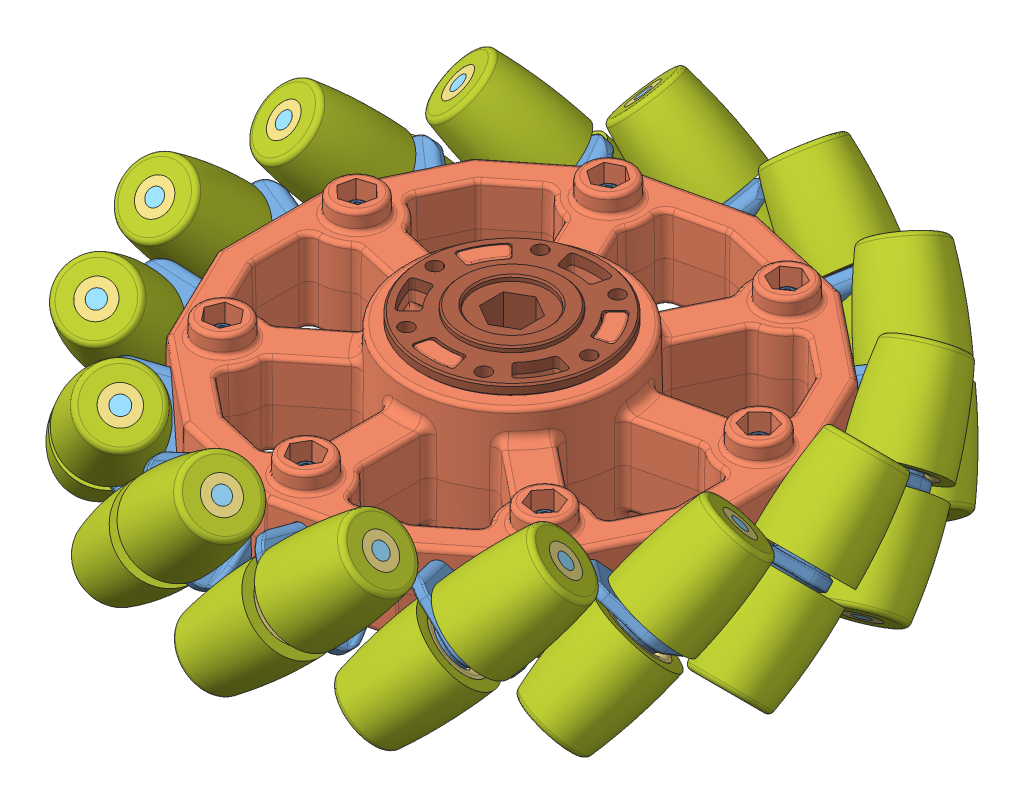
SolidWorks assembly 8in mecanum left vex 217-28011, configuration Default. Lengths in mm.
Overall size (213.38 67.99 218.38).
150 component instances, 12 part files, 7 mates.
Components (placement in the parent):
- 217-2799-002 Rev1_1-1: 217-2799-002 Rev1_1 [Default] at (67.5204 0 0) x (0 0 -1) z (1 0 0) size (26.84 25.28 30.09)
- 217-2801-001 Rev1_1-1: 217-2801-001 Rev1_1 [Default] at (-0.0396 6.3542 -0.0405) x (1 0 0) z (0 -1 0) size (148.4 151.99 28.55)
- 217-2801-001 Rev1_1-2: 217-2801-001 Rev1_1 [Default] at (-0.0396 -6.3458 -0.0405) x (-1 0 0) z (0 1 0) size (148.4 151.99 28.55)
- 217-2586-003 Rev2_1-1: 217-2586-003 Rev2_1 [Default] at (88.2976 -4.0062 4.0062) x (-0.854327 -0.367509 -0.367509) z (-0.519737 0.6041 0.6041) size (19.46 28.57 19.46)
- 217-2586-003 Rev2_1-2: 217-2586-003 Rev2_1 [Default] at (88.2976 4.0062 -4.0062) x (0.717269 -0.492709 -0.492709) z (0.696796 0.507186 0.507186) size (19.46 28.57 19.46)
- 217-2586-005 Rev2_1-1: 217-2586-005 Rev2_1 [Default] at (88.2976 -6.3286 6.3286) x (0 0.707107 -0.707107) z (0.473193 -0.622932 -0.622932) size (8.5 8 8)
- 217-2586-005 Rev2_1-2: 217-2586-005 Rev2_1 [Default] at (88.2976 6.3286 -6.3286) x (0 0.707107 -0.707107) z (0.707107 -0.5 -0.5) size (8.5 8 8)
- 217-2586-007 Rev1_1-1: 217-2586-007 Rev1_1 [Default] at (88.2976 0 0) x (0 0.707107 -0.707107) z (0.543569 -0.59352 -0.59352) size (61.72 5 5)
- 217-2586-008 Rev1_1-1: 217-2586-008 Rev1_1 [Default] at (-11.9459 2.5442 -20.6627) x (0.866025 0 -0.5) z (0 -1 0) size (7.33 6.35 31.75)
- 217-2587-002 Rev2_1-1: 217-2587-002 Rev2_1 [Default] at (88.2976 -0.3986 0.3986) x (-0.963241 0.189956 0.189956) z (-0.268638 -0.681114 -0.681114) size (26.1 28.57 26.1)
- 217-2587-002 Rev2_1-2: 217-2587-002 Rev2_1 [Default] at (88.2976 0.3986 -0.3986) x (0.779223 -0.443177 -0.443177) z (-0.626747 -0.550994 -0.550994) size (26.1 28.57 26.1)
- NUT-832-NYLOCK_1-1: NUT-832-NYLOCK_1 [Default] at (-49.6859 -13.6521 39.5511) x (-0.365341 0 0.930874) z (0.930874 0 0.365341) size (10.2 5.86 8.12)
- PINL-M050-0012-S_1-1: PINL-M050-0012-S_1 [Default] at (-69.318 -0.0958 -15.8528) x (0 -1 0) z (-0.272222 0 0.962235) size (12 5 5)
- SCREW-832-1250_1-1: SCREW-832-1250_1 [Default] at (-49.6859 14.914 39.5511) x (0 -1 0) z (-0.321403 0 -0.946943) size (33.96 7.92 7.92)
- 217-2586-008 Rev1_1-2: 217-2586-008 Rev1_1 [Default] at (-23.8521 2.5442 -0.0405) x (0 0 -1) z (0 -1 0) size (7.33 6.35 31.75)
- 217-2586-008 Rev1_1-3: 217-2586-008 Rev1_1 [Default] at (-11.9459 2.5442 20.5817) x (-0.866025 0 -0.5) z (0 -1 0) size (7.33 6.35 31.75)
- 217-2586-008 Rev1_1-4: 217-2586-008 Rev1_1 [Default] at (11.8666 2.5442 20.5817) x (-0.866025 0 0.5) z (0 -1 0) size (7.33 6.35 31.75)
- 217-2586-008 Rev1_1-5: 217-2586-008 Rev1_1 [Default] at (23.7729 2.5442 -0.0405) x (0 0 1) z (0 -1 0) size (7.33 6.35 31.75)
- 217-2586-008 Rev1_1-6: 217-2586-008 Rev1_1 [Default] at (11.8666 2.5442 -20.6627) x (0.866025 0 0.5) z (0 -1 0) size (7.33 6.35 31.75)
- NUT-832-NYLOCK_1-2: NUT-832-NYLOCK_1 [Default] at (-0.0396 -13.6521 63.4595) x (0.5 0 0.866025) z (0.866025 0 -0.5) size (10.2 5.86 8.12)
- NUT-832-NYLOCK_1-3: NUT-832-NYLOCK_1 [Default] at (49.6067 -13.6521 39.5511) x (0.988831 0 0.149042) z (0.149042 0 -0.988831) size (10.2 5.86 8.12)
- NUT-832-NYLOCK_1-4: NUT-832-NYLOCK_1 [Default] at (61.8683 -13.6521 -14.1706) x (0.733052 0 -0.680173) z (-0.680173 0 -0.733052) size (10.2 5.86 8.12)
- NUT-832-NYLOCK_1-5: NUT-832-NYLOCK_1 [Default] at (27.512 -13.6521 -57.252) x (-0.07473 0 -0.997204) z (-0.997204 0 0.07473) size (10.2 5.86 8.12)
- NUT-832-NYLOCK_1-6: NUT-832-NYLOCK_1 [Default] at (-27.5912 -13.6521 -57.252) x (-0.826239 0 -0.56332) z (-0.56332 0 0.826239) size (10.2 5.86 8.12)
- NUT-832-NYLOCK_1-7: NUT-832-NYLOCK_1 [Default] at (-61.9475 -13.6521 -14.1706) x (-0.955573 0 0.294755) z (0.294755 0 0.955573) size (10.2 5.86 8.12)
- SCREW-832-1250_1-2: SCREW-832-1250_1 [Default] at (-0.0396 14.914 63.4595) x (0 -1 0) z (-0.940741 0 -0.339126) size (33.96 7.92 7.92)
- SCREW-832-1250_1-3: SCREW-832-1250_1 [Default] at (49.6067 14.914 39.5511) x (0 -1 0) z (-0.851682 0 0.524059) size (33.96 7.92 7.92)
- SCREW-832-1250_1-4: SCREW-832-1250_1 [Default] at (61.8683 14.914 -14.1706) x (0 -1 0) z (-0.121289 0 0.992617) size (33.96 7.92 7.92)
- SCREW-832-1250_1-5: SCREW-832-1250_1 [Default] at (27.512 14.914 -57.252) x (0 -1 0) z (0.700437 0 0.713714) size (33.96 7.92 7.92)
- SCREW-832-1250_1-6: SCREW-832-1250_1 [Default] at (-27.5912 14.914 -57.252) x (0 -1 0) z (0.99472 0 -0.10263) size (33.96 7.92 7.92)
- SCREW-832-1250_1-7: SCREW-832-1250_1 [Default] at (-61.9475 14.914 -14.1706) x (0 -1 0) z (0.539958 0 -0.841692) size (33.96 7.92 7.92)
- PINL-M050-0012-S_1-2: PINL-M050-0012-S_1 [Default] at (-69.318 -0.0958 15.7719) x (0 -1 0) z (0.172235 0 0.985056) size (12 5 5)
- PINL-M050-0012-S_1-3: PINL-M050-0012-S_1 [Default] at (-55.5966 -0.0958 44.2647) x (0 -1 0) z (0.582578 0 0.812775) size (12 5 5)
- PINL-M050-0012-S_1-4: PINL-M050-0012-S_1 [Default] at (-30.8714 -0.0958 63.9824) x (0 -1 0) z (0.877534 0 0.479514) size (12 5 5)
- PINL-M050-0012-S_1-5: PINL-M050-0012-S_1 [Default] at (-0.0396 -0.0958 71.0195) x (0 -1 0) z (0.998684 0 0.051279) size (12 5 5)
- PINL-M050-0012-S_1-6: PINL-M050-0012-S_1 [Default] at (30.7922 -0.0958 63.9824) x (0 -1 0) z (0.922033 0 -0.387112) size (12 5 5)
- PINL-M050-0012-S_1-7: PINL-M050-0012-S_1 [Default] at (55.5173 -0.0958 44.2647) x (0 -1 0) z (0.662761 0 -0.748831) size (12 5 5)
- PINL-M050-0012-S_1-8: PINL-M050-0012-S_1 [Default] at (69.2388 -0.0958 15.7719) x (0 -1 0) z (0.272222 0 -0.962235) size (12 5 5)
- PINL-M050-0012-S_1-9: PINL-M050-0012-S_1 [Default] at (69.2388 -0.0958 -15.8528) x (0 -1 0) z (-0.172235 0 -0.985056) size (12 5 5)
- PINL-M050-0012-S_1-10: PINL-M050-0012-S_1 [Default] at (55.5173 -0.0958 -44.3457) x (0 -1 0) z (-0.582578 0 -0.812775) size (12 5 5)
- PINL-M050-0012-S_1-11: PINL-M050-0012-S_1 [Default] at (30.7922 -0.0958 -64.0633) x (0 -1 0) z (-0.877534 0 -0.479514) size (12 5 5)
- PINL-M050-0012-S_1-12: PINL-M050-0012-S_1 [Default] at (-0.0396 -0.0958 -71.1005) x (0 -1 0) z (-0.998684 0 -0.051279) size (12 5 5)
- PINL-M050-0012-S_1-13: PINL-M050-0012-S_1 [Default] at (-30.8714 -0.0958 -64.0633) x (0 -1 0) z (-0.922033 0 0.387112) size (12 5 5)
- PINL-M050-0012-S_1-14: PINL-M050-0012-S_1 [Default] at (-55.5966 -0.0958 -44.3457) x (0 -1 0) z (-0.662761 0 0.748831) size (12 5 5)
- 217-2587-002 Rev2_1-3: 217-2587-002 Rev2_1 [Default] at (79.3941 0.3986 -38.6912) x (0.509769 -0.443177 -0.737381) z (-0.803746 -0.550994 -0.224493) size (26.1 28.57 26.1)
- 217-2587-002 Rev2_1-4: 217-2587-002 Rev2_1 [Default] at (54.7578 0.3986 -69.3286) x (0.139348 -0.443177 -0.885537) z (-0.821555 -0.550994 0.146471) size (26.1 28.57 26.1)
- 217-2587-002 Rev2_1-5: 217-2587-002 Rev2_1 [Default] at (19.2682 0.3986 -86.2426) x (-0.258672 -0.443177 -0.858303) z (-0.676644 -0.550994 0.488425) size (26.1 28.57 26.1)
- 217-2587-002 Rev2_1-6: 217-2587-002 Rev2_1 [Default] at (-20.0456 0.3986 -86.0832) x (-0.605459 -0.443177 -0.66107) z (-0.397715 -0.550994 0.73364) size (26.1 28.57 26.1)
- 217-2587-002 Rev2_1-7: 217-2587-002 Rev2_1 [Default] at (-55.3969 0.3986 -68.882) x (-0.832327 -0.443177 -0.332905) z (-0.040014 -0.550994 0.833549) size (26.1 28.57 26.1)
- 217-2587-002 Rev2_1-8: 217-2587-002 Rev2_1 [Default] at (-79.784 0.3986 -38.0459) x (-0.894343 -0.443177 0.061196) z (0.325612 -0.550994 0.768364) size (26.1 28.57 26.1)
- 217-2587-002 Rev2_1-9: 217-2587-002 Rev2_1 [Default] at (-88.3768 0.3986 0.3176) x (-0.779223 -0.443177 0.443177) z (0.626747 -0.550994 0.550994) size (26.1 28.57 26.1)
- 217-2587-002 Rev2_1-10: 217-2587-002 Rev2_1 [Default] at (-79.4733 0.3986 38.6102) x (-0.509769 -0.443177 0.737381) z (0.803746 -0.550994 0.224493) size (26.1 28.57 26.1)
- 217-2587-002 Rev2_1-11: 217-2587-002 Rev2_1 [Default] at (-54.837 0.3986 69.2476) x (-0.139348 -0.443177 0.885537) z (0.821555 -0.550994 -0.146471) size (26.1 28.57 26.1)
- 217-2587-002 Rev2_1-12: 217-2587-002 Rev2_1 [Default] at (-19.3474 0.3986 86.1616) x (0.258672 -0.443177 0.858303) z (0.676644 -0.550994 -0.488425) size (26.1 28.57 26.1)
- 217-2587-002 Rev2_1-13: 217-2587-002 Rev2_1 [Default] at (19.9664 0.3986 86.0022) x (0.605459 -0.443177 0.66107) z (0.397715 -0.550994 -0.73364) size (26.1 28.57 26.1)
- 217-2587-002 Rev2_1-14: 217-2587-002 Rev2_1 [Default] at (55.3177 0.3986 68.8011) x (0.832327 -0.443177 0.332905) z (0.040014 -0.550994 -0.833549) size (26.1 28.57 26.1)
- 217-2587-002 Rev2_1-15: 217-2587-002 Rev2_1 [Default] at (79.7048 0.3986 37.965) x (0.894343 -0.443177 -0.061196) z (-0.325612 -0.550994 -0.768364) size (26.1 28.57 26.1)
- 217-2587-002 Rev2_1-16: 217-2587-002 Rev2_1 [Default] at (79.74 -0.3986 -37.973) x (-0.785432 0.189956 0.589079) z (-0.537559 -0.681114 -0.497105) size (26.1 28.57 26.1)
- 217-2587-002 Rev2_1-17: 217-2587-002 Rev2_1 [Default] at (55.381 -0.3986 -68.8315) x (-0.452058 0.189956 0.871528) z (-0.70001 -0.681114 -0.214638) size (26.1 28.57 26.1)
- 217-2587-002 Rev2_1-18: 217-2587-002 Rev2_1 [Default] at (20.0453 -0.3986 -86.0652) x (-0.029148 0.189956 0.98136) z (-0.723815 -0.681114 0.110341) size (26.1 28.57 26.1)
- 217-2587-002 Rev2_1-19: 217-2587-002 Rev2_1 [Default] at (-19.2684 -0.3986 -86.2606) x (0.399535 0.189956 0.896822) z (-0.60426 -0.681114 0.413465) size (26.1 28.57 26.1)
- 217-2587-002 Rev2_1-20: 217-2587-002 Rev2_1 [Default] at (-54.7737 -0.3986 -69.379) x (0.749084 0.189956 0.634657) z (-0.365024 -0.681114 0.634698) size (26.1 28.57 26.1)
- 217-2587-002 Rev2_1-21: 217-2587-002 Rev2_1 [Default] at (-79.4382 -0.3986 -38.7641) x (0.950269 0.189956 0.24679) z (-0.05349 -0.681114 0.730221) size (26.1 28.57 26.1)
- 217-2587-002 Rev2_1-22: 217-2587-002 Rev2_1 [Default] at (-88.3768 -0.3986 -0.4795) x (0.963241 0.189956 -0.189956) z (0.268638 -0.681114 0.681114) size (26.1 28.57 26.1)
- 217-2587-002 Rev2_1-23: 217-2587-002 Rev2_1 [Default] at (-79.8192 -0.3986 37.892) x (0.785432 0.189956 -0.589079) z (0.537559 -0.681114 0.497105) size (26.1 28.57 26.1)
- 217-2587-002 Rev2_1-24: 217-2587-002 Rev2_1 [Default] at (-55.4602 -0.3986 68.7506) x (0.452058 0.189956 -0.871528) z (0.70001 -0.681114 0.214638) size (26.1 28.57 26.1)
- 217-2587-002 Rev2_1-25: 217-2587-002 Rev2_1 [Default] at (-20.1245 -0.3986 85.9842) x (0.029148 0.189956 -0.98136) z (0.723815 -0.681114 -0.110341) size (26.1 28.57 26.1)
- 217-2587-002 Rev2_1-26: 217-2587-002 Rev2_1 [Default] at (19.1892 -0.3986 86.1796) x (-0.399535 0.189956 -0.896822) z (0.60426 -0.681114 -0.413465) size (26.1 28.57 26.1)
- 217-2587-002 Rev2_1-27: 217-2587-002 Rev2_1 [Default] at (54.6945 -0.3986 69.2981) x (-0.749084 0.189956 -0.634657) z (0.365024 -0.681114 -0.634698) size (26.1 28.57 26.1)
- 217-2587-002 Rev2_1-28: 217-2587-002 Rev2_1 [Default] at (79.359 -0.3986 38.6832) x (-0.950269 0.189956 -0.24679) z (0.05349 -0.681114 -0.730221) size (26.1 28.57 26.1)
- 217-2586-007 Rev1_1-2: 217-2586-007 Rev1_1 [Default] at (79.567 0 -38.3321) x (-0.306802 0.707107 -0.637081) z (0.23222 -0.59352 -0.770589) size (61.72 5 5)
- 217-2586-007 Rev1_1-3: 217-2586-007 Rev1_1 [Default] at (55.0694 0 -69.08) x (-0.552838 0.707107 -0.440874) z (-0.125123 -0.59352 -0.795033) size (61.72 5 5)
- 217-2586-007 Rev1_1-4: 217-2586-007 Rev1_1 [Default] at (19.6567 0 -86.1539) x (-0.689378 0.707107 -0.157346) z (-0.457684 -0.59352 -0.662011) size (61.72 5 5)
- 217-2586-007 Rev1_1-5: 217-2586-007 Rev1_1 [Default] at (-19.657 0 -86.1719) x (-0.689378 0.707107 0.157346) z (-0.699595 -0.59352 -0.39787) size (61.72 5 5)
- 217-2586-007 Rev1_1-6: 217-2586-007 Rev1_1 [Default] at (-55.0853 0 -69.1305) x (-0.552838 0.707107 0.440874) z (-0.802943 -0.59352 -0.054926) size (61.72 5 5)
- 217-2586-007 Rev1_1-7: 217-2586-007 Rev1_1 [Default] at (-79.6111 0 -38.405) x (-0.306802 0.707107 0.637081) z (-0.747258 -0.59352 0.298897) size (61.72 5 5)
- 217-2586-007 Rev1_1-8: 217-2586-007 Rev1_1 [Default] at (-88.3768 0 -0.081) x (0 0.707107 0.707107) z (-0.543569 -0.59352 0.59352) size (61.72 5 5)
- 217-2586-007 Rev1_1-9: 217-2586-007 Rev1_1 [Default] at (-79.6462 0 38.2511) x (0.306802 0.707107 0.637081) z (-0.23222 -0.59352 0.770589) size (61.72 5 5)
- 217-2586-007 Rev1_1-10: 217-2586-007 Rev1_1 [Default] at (-55.1486 0 68.9991) x (0.552838 0.707107 0.440874) z (0.125123 -0.59352 0.795033) size (61.72 5 5)
- 217-2586-007 Rev1_1-11: 217-2586-007 Rev1_1 [Default] at (-19.736 0 86.0729) x (0.689378 0.707107 0.157346) z (0.457684 -0.59352 0.662011) size (61.72 5 5)
- 217-2586-007 Rev1_1-12: 217-2586-007 Rev1_1 [Default] at (19.5778 0 86.0909) x (0.689378 0.707107 -0.157346) z (0.699595 -0.59352 0.39787) size (61.72 5 5)
- 217-2586-007 Rev1_1-13: 217-2586-007 Rev1_1 [Default] at (55.0061 0 69.0496) x (0.552838 0.707107 -0.440874) z (0.802943 -0.59352 0.054926) size (61.72 5 5)
- 217-2586-007 Rev1_1-14: 217-2586-007 Rev1_1 [Default] at (79.5319 0 38.3241) x (0.306802 0.707107 -0.637081) z (0.747258 -0.59352 -0.298897) size (61.72 5 5)
- 217-2586-005 Rev2_1-3: 217-2586-005 Rev2_1 [Default] at (76.8211 6.3286 -44.034) x (-0.306802 0.707107 -0.637081) z (0.420139 -0.5 -0.757287) size (8.5 8 8)
- 217-2586-005 Rev2_1-4: 217-2586-005 Rev2_1 [Default] at (50.1215 6.3286 -73.0259) x (-0.552838 0.707107 -0.440874) z (0.049958 -0.5 -0.864583) size (8.5 8 8)
- 217-2586-005 Rev2_1-5: 217-2586-005 Rev2_1 [Default] at (13.4868 6.3286 -87.5621) x (-0.689378 0.707107 -0.157346) z (-0.330118 -0.5 -0.800639) size (8.5 8 8)
- 217-2586-005 Rev2_1-6: 217-2586-005 Rev2_1 [Default] at (-25.827 6.3286 -84.7636) x (-0.689378 0.707107 0.157346) z (-0.64481 -0.5 -0.578118) size (8.5 8 8)
- 217-2586-005 Rev2_1-7: 217-2586-005 Rev2_1 [Default] at (-60.0332 6.3286 -65.1847) x (-0.552838 0.707107 0.440874) z (-0.83179 -0.5 -0.241093) size (8.5 8 8)
- 217-2586-005 Rev2_1-8: 217-2586-005 Rev2_1 [Default] at (-82.357 6.3286 -32.7032) x (-0.306802 0.707107 0.637081) z (-0.854023 -0.5 0.143682) size (8.5 8 8)
- 217-2586-005 Rev2_1-9: 217-2586-005 Rev2_1 [Default] at (-88.3768 6.3286 6.2476) x (0 0.707107 0.707107) z (-0.707107 -0.5 0.5) size (8.5 8 8)
- 217-2586-005 Rev2_1-10: 217-2586-005 Rev2_1 [Default] at (-76.9004 6.3286 43.953) x (0.306802 0.707107 0.637081) z (-0.420139 -0.5 0.757287) size (8.5 8 8)
- 217-2586-005 Rev2_1-11: 217-2586-005 Rev2_1 [Default] at (-50.2007 6.3286 72.9449) x (0.552838 0.707107 0.440874) z (-0.049958 -0.5 0.864583) size (8.5 8 8)
- 217-2586-005 Rev2_1-12: 217-2586-005 Rev2_1 [Default] at (-13.566 6.3286 87.4812) x (0.689378 0.707107 0.157346) z (0.330118 -0.5 0.800639) size (8.5 8 8)
- 217-2586-005 Rev2_1-13: 217-2586-005 Rev2_1 [Default] at (25.7477 6.3286 84.6827) x (0.689378 0.707107 -0.157346) z (0.64481 -0.5 0.578118) size (8.5 8 8)
- 217-2586-005 Rev2_1-14: 217-2586-005 Rev2_1 [Default] at (59.954 6.3286 65.1037) x (0.552838 0.707107 -0.440874) z (0.83179 -0.5 0.241093) size (8.5 8 8)
- 217-2586-005 Rev2_1-15: 217-2586-005 Rev2_1 [Default] at (82.2778 6.3286 32.6222) x (0.306802 0.707107 -0.637081) z (0.854023 -0.5 -0.143682) size (8.5 8 8)
- 217-2586-005 Rev2_1-16: 217-2586-005 Rev2_1 [Default] at (82.3129 -6.3286 -32.6302) x (-0.306802 0.707107 -0.637081) z (0.156052 -0.622932 -0.766553) size (8.5 8 8)
- 217-2586-005 Rev2_1-17: 217-2586-005 Rev2_1 [Default] at (60.0173 -6.3286 -65.1342) x (-0.552838 0.707107 -0.440874) z (-0.191997 -0.622932 -0.758349) size (8.5 8 8)
- 217-2586-005 Rev2_1-18: 217-2586-005 Rev2_1 [Default] at (25.8267 -6.3286 -84.7456) x (-0.689378 0.707107 -0.157346) z (-0.502019 -0.622932 -0.599944) size (8.5 8 8)
- 217-2586-005 Rev2_1-19: 217-2586-005 Rev2_1 [Default] at (-13.4871 -6.3286 -87.5801) x (-0.689378 0.707107 0.157346) z (-0.712609 -0.622932 -0.322713) size (8.5 8 8)
- 217-2586-005 Rev2_1-20: 217-2586-005 Rev2_1 [Default] at (-50.1374 -6.3286 -73.0764) x (-0.552838 0.707107 0.440874) z (-0.782059 -0.622932 0.018435) size (8.5 8 8)
- 217-2586-005 Rev2_1-21: 217-2586-005 Rev2_1 [Default] at (-76.8652 -6.3286 -44.1069) x (-0.306802 0.707107 0.637081) z (-0.696612 -0.622932 0.355932) size (8.5 8 8)
- 217-2586-005 Rev2_1-22: 217-2586-005 Rev2_1 [Default] at (-88.3768 -6.3286 -6.4096) x (0 0.707107 0.707107) z (-0.473193 -0.622932 0.622932) size (8.5 8 8)
- 217-2586-005 Rev2_1-23: 217-2586-005 Rev2_1 [Default] at (-82.3921 -6.3286 32.5492) x (0.306802 0.707107 0.637081) z (-0.156052 -0.622932 0.766553) size (8.5 8 8)
- 217-2586-005 Rev2_1-24: 217-2586-005 Rev2_1 [Default] at (-60.0965 -6.3286 65.0533) x (0.552838 0.707107 0.440874) z (0.191997 -0.622932 0.758349) size (8.5 8 8)
- 217-2586-005 Rev2_1-25: 217-2586-005 Rev2_1 [Default] at (-25.9059 -6.3286 84.6647) x (0.689378 0.707107 0.157346) z (0.502019 -0.622932 0.599944) size (8.5 8 8)
- 217-2586-005 Rev2_1-26: 217-2586-005 Rev2_1 [Default] at (13.4079 -6.3286 87.4992) x (0.689378 0.707107 -0.157346) z (0.712609 -0.622932 0.322713) size (8.5 8 8)
- 217-2586-005 Rev2_1-27: 217-2586-005 Rev2_1 [Default] at (50.0582 -6.3286 72.9954) x (0.552838 0.707107 -0.440874) z (0.782059 -0.622932 -0.018435) size (8.5 8 8)
- 217-2586-005 Rev2_1-28: 217-2586-005 Rev2_1 [Default] at (76.786 -6.3286 44.0259) x (0.306802 0.707107 -0.637081) z (0.696612 -0.622932 -0.355932) size (8.5 8 8)
- 217-2586-003 Rev2_1-3: 217-2586-003 Rev2_1 [Default] at (77.8288 4.0062 -41.9416) x (0.432459 -0.492709 -0.755127) z (0.847851 0.507186 0.15463) size (19.46 28.57 19.46)
- 217-2586-003 Rev2_1-4: 217-2586-003 Rev2_1 [Default] at (51.9372 4.0062 -71.5779) x (0.061995 -0.492709 -0.867983) z (0.830979 0.507186 -0.228552) size (19.46 28.57 19.46)
- 217-2586-003 Rev2_1-5: 217-2586-003 Rev2_1 [Default] at (15.7509 4.0062 -87.0453) x (-0.320749 -0.492709 -0.808924) z (0.649521 0.507186 -0.566466) size (19.46 28.57 19.46)
- 217-2586-003 Rev2_1-6: 217-2586-003 Rev2_1 [Default] at (-23.5628 4.0062 -85.2804) x (-0.639963 -0.492709 -0.589648) z (0.339418 0.507186 -0.792185) size (19.46 28.57 19.46)
- 217-2586-003 Rev2_1-7: 217-2586-003 Rev2_1 [Default] at (-58.2175 4.0062 -66.6327) x (-0.832426 -0.492709 -0.253585) z (-0.037911 0.507186 -0.861002) size (19.46 28.57 19.46)
- 217-2586-003 Rev2_1-8: 217-2586-003 Rev2_1 [Default] at (-81.3494 4.0062 -34.7955) x (-0.860016 -0.492709 0.132704) z (-0.407732 0.507186 -0.759287) size (19.46 28.57 19.46)
- 217-2586-003 Rev2_1-9: 217-2586-003 Rev2_1 [Default] at (-88.3768 4.0062 3.9253) x (-0.717269 -0.492709 0.492709) z (-0.696796 0.507186 -0.507186) size (19.46 28.57 19.46)
- 217-2586-003 Rev2_1-10: 217-2586-003 Rev2_1 [Default] at (-77.908 4.0062 41.8606) x (-0.432459 -0.492709 0.755127) z (-0.847851 0.507186 -0.15463) size (19.46 28.57 19.46)
- 217-2586-003 Rev2_1-11: 217-2586-003 Rev2_1 [Default] at (-52.0164 4.0062 71.4969) x (-0.061995 -0.492709 0.867983) z (-0.830979 0.507186 0.228552) size (19.46 28.57 19.46)
- 217-2586-003 Rev2_1-12: 217-2586-003 Rev2_1 [Default] at (-15.8302 4.0062 86.9644) x (0.320749 -0.492709 0.808924) z (-0.649521 0.507186 0.566466) size (19.46 28.57 19.46)
- 217-2586-003 Rev2_1-13: 217-2586-003 Rev2_1 [Default] at (23.4836 4.0062 85.1995) x (0.639963 -0.492709 0.589648) z (-0.339418 0.507186 0.792185) size (19.46 28.57 19.46)
- 217-2586-003 Rev2_1-14: 217-2586-003 Rev2_1 [Default] at (58.1383 4.0062 66.5517) x (0.832426 -0.492709 0.253585) z (0.037911 0.507186 0.861002) size (19.46 28.57 19.46)
- 217-2586-003 Rev2_1-15: 217-2586-003 Rev2_1 [Default] at (81.2701 4.0062 34.7146) x (0.860016 -0.492709 -0.132704) z (0.407732 0.507186 0.759287) size (19.46 28.57 19.46)
- 217-2586-003 Rev2_1-16: 217-2586-003 Rev2_1 [Default] at (81.3053 -4.0062 -34.7226) x (-0.929178 -0.367509 0.039564) z (-0.206157 0.6041 0.769781) size (19.46 28.57 19.46)
- 217-2586-003 Rev2_1-17: 217-2586-003 Rev2_1 [Default] at (58.2016 -4.0062 -66.5822) x (-0.819994 -0.367509 0.438801) z (0.148254 0.6041 0.782997) size (19.46 28.57 19.46)
- 217-2586-003 Rev2_1-18: 217-2586-003 Rev2_1 [Default] at (23.5625 -4.0062 -85.2624) x (-0.548401 -0.367509 0.751128) z (0.473302 0.6041 0.641131) size (19.46 28.57 19.46)
- 217-2586-003 Rev2_1-19: 217-2586-003 Rev2_1 [Default] at (-15.7512 -4.0062 -87.0634) x (-0.16819 -0.367509 0.914685) z (0.704606 0.6041 0.372281) size (19.46 28.57 19.46)
- 217-2586-003 Rev2_1-20: 217-2586-003 Rev2_1 [Default] at (-51.9531 -4.0062 -71.6284) x (0.245334 -0.367509 0.897078) z (0.796355 0.6041 0.029696) size (19.46 28.57 19.46)
- 217-2586-003 Rev2_1-21: 217-2586-003 Rev2_1 [Default] at (-77.8729 -4.0062 -42.0145) x (0.610265 -0.367509 0.701793) z (0.730376 0.6041 -0.31877) size (19.46 28.57 19.46)
- 217-2586-003 Rev2_1-22: 217-2586-003 Rev2_1 [Default] at (-88.3768 -4.0062 -4.0872) x (0.854327 -0.367509 0.367509) z (0.519737 0.6041 -0.6041) size (19.46 28.57 19.46)
- 217-2586-003 Rev2_1-23: 217-2586-003 Rev2_1 [Default] at (-81.3845 -4.0062 34.6416) x (0.929178 -0.367509 -0.039564) z (0.206157 0.6041 -0.769781) size (19.46 28.57 19.46)
- 217-2586-003 Rev2_1-24: 217-2586-003 Rev2_1 [Default] at (-58.2808 -4.0062 66.5012) x (0.819994 -0.367509 -0.438801) z (-0.148254 0.6041 -0.782997) size (19.46 28.57 19.46)
- 217-2586-003 Rev2_1-25: 217-2586-003 Rev2_1 [Default] at (-23.6417 -4.0062 85.1814) x (0.548401 -0.367509 -0.751128) z (-0.473302 0.6041 -0.641131) size (19.46 28.57 19.46)
- 217-2586-003 Rev2_1-26: 217-2586-003 Rev2_1 [Default] at (15.672 -4.0062 86.9824) x (0.16819 -0.367509 -0.914685) z (-0.704606 0.6041 -0.372281) size (19.46 28.57 19.46)
- 217-2586-003 Rev2_1-27: 217-2586-003 Rev2_1 [Default] at (51.8739 -4.0062 71.5474) x (-0.245334 -0.367509 -0.897078) z (-0.796355 0.6041 -0.029696) size (19.46 28.57 19.46)
- 217-2586-003 Rev2_1-28: 217-2586-003 Rev2_1 [Default] at (77.7937 -4.0062 41.9336) x (-0.610265 -0.367509 -0.701793) z (-0.730376 0.6041 0.31877) size (19.46 28.57 19.46)
- 217-2799-002 Rev1_1-2: 217-2799-002 Rev1_1 [Default] at (60.8474 0 -29.3172) x (-0.433884 0 -0.900969) z (0.900969 0 -0.433884) size (26.84 25.28 30.09)
- 217-2799-002 Rev1_1-3: 217-2799-002 Rev1_1 [Default] at (42.115 0 -52.8358) x (-0.781831 0 -0.62349) z (0.62349 0 -0.781831) size (26.84 25.28 30.09)
- 217-2799-002 Rev1_1-4: 217-2799-002 Rev1_1 [Default] at (15.0334 0 -65.8976) x (-0.974928 0 -0.222521) z (0.222521 0 -0.974928) size (26.84 25.28 30.09)
- 217-2799-002 Rev1_1-5: 217-2799-002 Rev1_1 [Default] at (-15.0337 0 -65.9156) x (-0.974928 0 0.222521) z (-0.222521 0 -0.974928) size (26.84 25.28 30.09)
- 217-2799-002 Rev1_1-6: 217-2799-002 Rev1_1 [Default] at (-42.1309 0 -52.8863) x (-0.781831 0 0.62349) z (-0.62349 0 -0.781831) size (26.84 25.28 30.09)
- 217-2799-002 Rev1_1-7: 217-2799-002 Rev1_1 [Default] at (-60.8915 0 -29.3901) x (-0.433884 0 0.900969) z (-0.900969 0 -0.433884) size (26.84 25.28 30.09)
- 217-2799-002 Rev1_1-8: 217-2799-002 Rev1_1 [Default] at (-67.5996 0 -0.081) x (0 0 1) z (-1 0 0) size (26.84 25.28 30.09)
- 217-2799-002 Rev1_1-9: 217-2799-002 Rev1_1 [Default] at (-60.9266 0 29.2362) x (0.433884 0 0.900969) z (-0.900969 0 0.433884) size (26.84 25.28 30.09)
- 217-2799-002 Rev1_1-10: 217-2799-002 Rev1_1 [Default] at (-42.1942 0 52.7548) x (0.781831 0 0.62349) z (-0.62349 0 0.781831) size (26.84 25.28 30.09)
- 217-2799-002 Rev1_1-11: 217-2799-002 Rev1_1 [Default] at (-15.1126 0 65.8166) x (0.974928 0 0.222521) z (-0.222521 0 0.974928) size (26.84 25.28 30.09)
- 217-2799-002 Rev1_1-12: 217-2799-002 Rev1_1 [Default] at (14.9544 0 65.8347) x (0.974928 0 -0.222521) z (0.222521 0 0.974928) size (26.84 25.28 30.09)
- 217-2799-002 Rev1_1-13: 217-2799-002 Rev1_1 [Default] at (42.0517 0 52.8053) x (0.781831 0 -0.62349) z (0.62349 0 0.781831) size (26.84 25.28 30.09)
- 217-2799-002 Rev1_1-14: 217-2799-002 Rev1_1 [Default] at (60.8123 0 29.3092) x (0.433884 0 -0.900969) z (0.900969 0 0.433884) size (26.84 25.28 30.09)
- Versahub 0.5in hex-1: Versahub 0.5in hex [Default] at (-0.0396 12.0692 -0.0405) x (0 1 0) z (0 0 1) size (14.3 55.88 55.88)
- 0.5in hex bearing-1: 0.5in hex bearing [Default] at (-0.0396 -15.2358 -0.0405) x (0.866025 0 0.5) z (0 -1 0) size (31.12 31.12 7.94)
Mates (geometry in assembly coordinates):
- Coincident1: coincident anti-aligned: plane of 217-2801-001 Rev1_1-2 through (-0.0396 21.5942 -0.0405) normal (0 1 0); plane of Versahub 0.5in hex-1 through (-14.3345 21.5942 -0.0405) normal (0 -1 0)
- Concentric1: concentric aligned: cylinder of 217-2801-001 Rev1_1-2 through (-0.0396 21.5942 -0.0405) axis (0 -1 0) radius 14.3; cylinder of Versahub 0.5in hex-1 through (-0.0396 12.0692 -0.0405) axis (0 -1 0) radius 14.295
- Parallel1: parallel anti-aligned: cylinder of 217-2801-001 Rev1_1-2 through (-23.8521 18.4192 -0.0405) axis (0 1 0) radius 2.1526; cylinder of Versahub 0.5in hex-1 through (-23.8546 21.5942 -0.0405) axis (0 -1 0) radius 2.15
- Parallel2: parallel anti-aligned: plane of 217-2801-001 Rev1_1-2 through (-18.0708 24.7692 -18.0717) normal (0.707107 0 -0.707107); plane of Versahub 0.5in hex-1 through (-18.0354 21.5942 -18.107) normal (-0.707107 0 0.707107)
- Coincident4: coincident aligned: plane of 217-2801-001 Rev1_1-1 through (-0.0396 -21.5858 -0.0405) normal (0 -1 0); circle of 0.5in hex bearing-1
- Concentric5: concentric aligned: cylinder of 217-2801-001 Rev1_1-1 through (-0.0396 -21.5858 -0.0405) axis (0 1 0) radius 14.3; cylinder of 0.5in hex bearing-1 through (-0.0396 -21.5858 -0.0405) axis (0 1 0) radius 14.2748
- Parallel3: parallel aligned: plane of Versahub 0.5in hex-1 through (-0.0396 12.0692 7.3065) normal (-0.5 0 -0.866025); plane of 0.5in hex bearing-1 through (-0.0396 -23.1733 7.2919) normal (-0.5 0 -0.866025)
